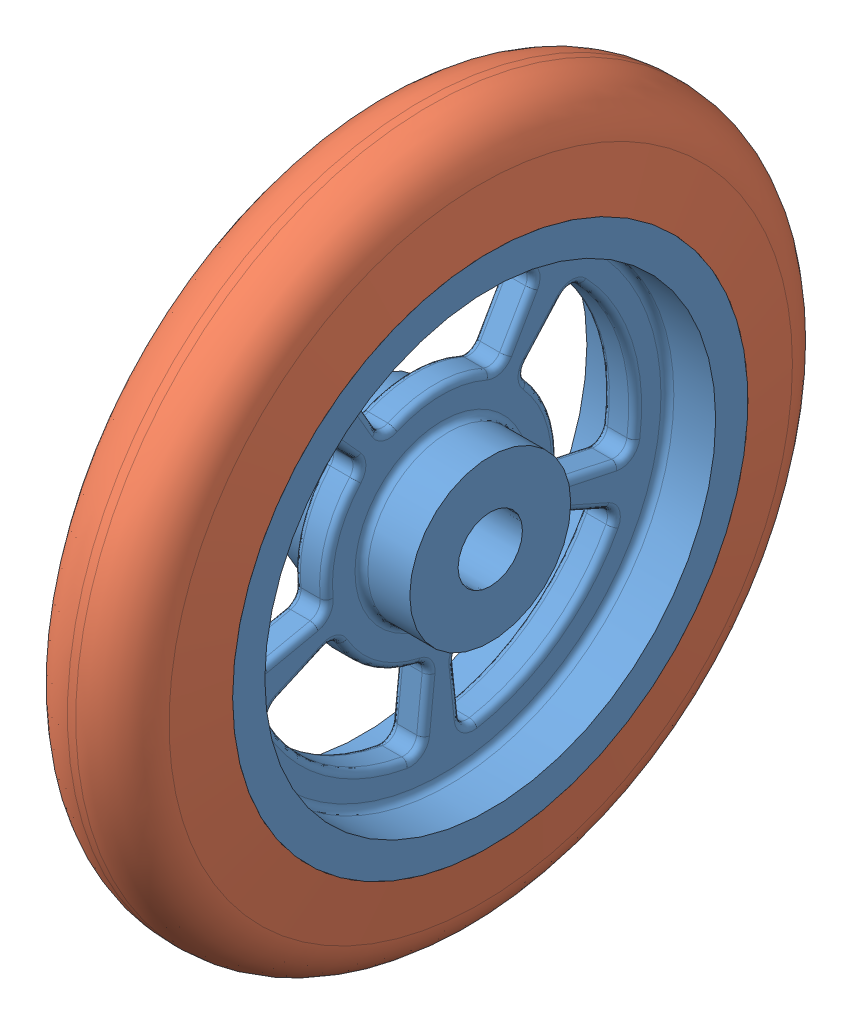
SolidWorks assembly Assem1, configuration Default. Lengths in mm.
Overall size (20 110 110).
2 component instances, 2 part files, 1 mates.
Components (placement in the parent):
- Wheel.SLDPART-1: Wheel.SLDPART [Default] at (23.415 45.1517 62.4965) size (20 80 80)
- Tire.SLDPART-1: Tire.SLDPART [Default] at (23.415 45.1517 62.4965) size (20 110 110)
Mates (geometry in assembly coordinates):
- Coincident1: coincident aligned: circle of Wheel.SLDPART-1; circle of Tire.SLDPART-1
